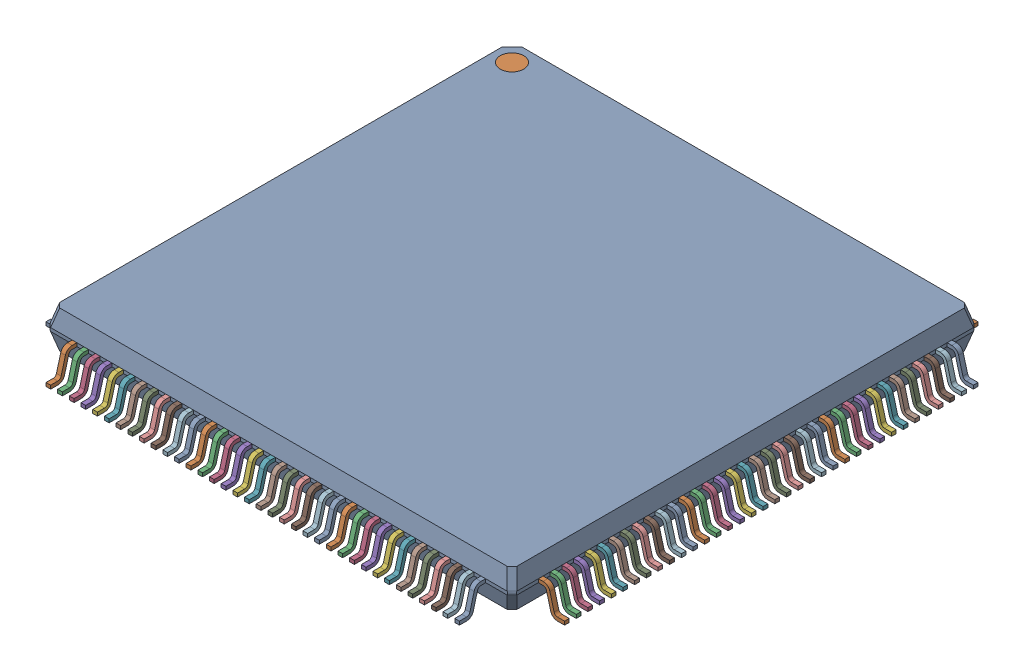
SolidWorks assembly User Library-LQFP144-3, configuration 默认. Lengths in mm.
Overall size (22.2 1.89 22.2).
146 component instances, 3 part files, 0 mates.
Components (placement in the parent):
- case-1: case [默认] at (0 1 0) size (19.96 1.6 19.96)
- pin-28-1: pin-28 [默认] at (-8.75 0.9224 9.9806) size (0.2 1.16 1.12)
- pin-28-2: pin-28 [默认] at (-8.25 0.9224 9.9806) size (0.2 1.16 1.12)
- pin-28-3: pin-28 [默认] at (-7.75 0.9224 9.9806) size (0.2 1.16 1.12)
- pin-28-4: pin-28 [默认] at (-7.25 0.9224 9.9806) size (0.2 1.16 1.12)
- pin-28-5: pin-28 [默认] at (-6.75 0.9224 9.9806) size (0.2 1.16 1.12)
- pin-28-6: pin-28 [默认] at (-6.25 0.9224 9.9806) size (0.2 1.16 1.12)
- pin-28-7: pin-28 [默认] at (-5.75 0.9224 9.9806) size (0.2 1.16 1.12)
- pin-28-8: pin-28 [默认] at (-5.25 0.9224 9.9806) size (0.2 1.16 1.12)
- pin-28-9: pin-28 [默认] at (-4.75 0.9224 9.9806) size (0.2 1.16 1.12)
- pin-28-10: pin-28 [默认] at (-4.25 0.9224 9.9806) size (0.2 1.16 1.12)
- pin-28-11: pin-28 [默认] at (-3.75 0.9224 9.9806) size (0.2 1.16 1.12)
- pin-28-12: pin-28 [默认] at (-3.25 0.9224 9.9806) size (0.2 1.16 1.12)
- pin-28-13: pin-28 [默认] at (-2.75 0.9224 9.9806) size (0.2 1.16 1.12)
- pin-28-14: pin-28 [默认] at (-2.25 0.9224 9.9806) size (0.2 1.16 1.12)
- pin-28-15: pin-28 [默认] at (-1.75 0.9224 9.9806) size (0.2 1.16 1.12)
- pin-28-16: pin-28 [默认] at (-1.25 0.9224 9.9806) size (0.2 1.16 1.12)
- pin-28-17: pin-28 [默认] at (-0.75 0.9224 9.9806) size (0.2 1.16 1.12)
- pin-28-18: pin-28 [默认] at (-0.25 0.9224 9.9806) size (0.2 1.16 1.12)
- pin-28-19: pin-28 [默认] at (0.25 0.9224 9.9806) size (0.2 1.16 1.12)
- pin-28-20: pin-28 [默认] at (0.75 0.9224 9.9806) size (0.2 1.16 1.12)
- pin-28-21: pin-28 [默认] at (1.25 0.9224 9.9806) size (0.2 1.16 1.12)
- pin-28-22: pin-28 [默认] at (1.75 0.9224 9.9806) size (0.2 1.16 1.12)
- pin-28-23: pin-28 [默认] at (2.25 0.9224 9.9806) size (0.2 1.16 1.12)
- pin-28-24: pin-28 [默认] at (2.75 0.9224 9.9806) size (0.2 1.16 1.12)
- pin-28-25: pin-28 [默认] at (3.25 0.9224 9.9806) size (0.2 1.16 1.12)
- pin-28-26: pin-28 [默认] at (3.75 0.9224 9.9806) size (0.2 1.16 1.12)
- pin-28-27: pin-28 [默认] at (4.25 0.9224 9.9806) size (0.2 1.16 1.12)
- pin-28-28: pin-28 [默认] at (4.75 0.9224 9.9806) size (0.2 1.16 1.12)
- pin-28-29: pin-28 [默认] at (5.25 0.9224 9.9806) size (0.2 1.16 1.12)
- pin-28-30: pin-28 [默认] at (5.75 0.9224 9.9806) size (0.2 1.16 1.12)
- pin-28-31: pin-28 [默认] at (6.25 0.9224 9.9806) size (0.2 1.16 1.12)
- pin-28-32: pin-28 [默认] at (6.75 0.9224 9.9806) size (0.2 1.16 1.12)
- pin-28-33: pin-28 [默认] at (7.25 0.9224 9.9806) size (0.2 1.16 1.12)
- pin-28-34: pin-28 [默认] at (7.75 0.9224 9.9806) size (0.2 1.16 1.12)
- pin-28-35: pin-28 [默认] at (8.25 0.9224 9.9806) size (0.2 1.16 1.12)
- pin-28-36: pin-28 [默认] at (8.75 0.9224 9.9806) size (0.2 1.16 1.12)
- pin-28-37: pin-28 [默认] at (9.9806 0.9224 8.75) x (0 0 -1) z (1 0 0) size (0.2 1.16 1.12)
- pin-28-38: pin-28 [默认] at (9.9806 0.9224 8.25) x (0 0 -1) z (1 0 0) size (0.2 1.16 1.12)
- pin-28-39: pin-28 [默认] at (9.9806 0.9224 7.75) x (0 0 -1) z (1 0 0) size (0.2 1.16 1.12)
- pin-28-40: pin-28 [默认] at (9.9806 0.9224 7.25) x (0 0 -1) z (1 0 0) size (0.2 1.16 1.12)
- pin-28-41: pin-28 [默认] at (9.9806 0.9224 6.75) x (0 0 -1) z (1 0 0) size (0.2 1.16 1.12)
- pin-28-42: pin-28 [默认] at (9.9806 0.9224 6.25) x (0 0 -1) z (1 0 0) size (0.2 1.16 1.12)
- pin-28-43: pin-28 [默认] at (9.9806 0.9224 5.75) x (0 0 -1) z (1 0 0) size (0.2 1.16 1.12)
- pin-28-44: pin-28 [默认] at (9.9806 0.9224 5.25) x (0 0 -1) z (1 0 0) size (0.2 1.16 1.12)
- pin-28-45: pin-28 [默认] at (9.9806 0.9224 4.75) x (0 0 -1) z (1 0 0) size (0.2 1.16 1.12)
- pin-28-46: pin-28 [默认] at (9.9806 0.9224 4.25) x (0 0 -1) z (1 0 0) size (0.2 1.16 1.12)
- pin-28-47: pin-28 [默认] at (9.9806 0.9224 3.75) x (0 0 -1) z (1 0 0) size (0.2 1.16 1.12)
- pin-28-48: pin-28 [默认] at (9.9806 0.9224 3.25) x (0 0 -1) z (1 0 0) size (0.2 1.16 1.12)
- pin-28-49: pin-28 [默认] at (9.9806 0.9224 2.75) x (0 0 -1) z (1 0 0) size (0.2 1.16 1.12)
- pin-28-50: pin-28 [默认] at (9.9806 0.9224 2.25) x (0 0 -1) z (1 0 0) size (0.2 1.16 1.12)
- pin-28-51: pin-28 [默认] at (9.9806 0.9224 1.75) x (0 0 -1) z (1 0 0) size (0.2 1.16 1.12)
- pin-28-52: pin-28 [默认] at (9.9806 0.9224 1.25) x (0 0 -1) z (1 0 0) size (0.2 1.16 1.12)
- pin-28-53: pin-28 [默认] at (9.9806 0.9224 0.75) x (0 0 -1) z (1 0 0) size (0.2 1.16 1.12)
- pin-28-54: pin-28 [默认] at (9.9806 0.9224 0.25) x (0 0 -1) z (1 0 0) size (0.2 1.16 1.12)
- pin-28-55: pin-28 [默认] at (9.9806 0.9224 -0.25) x (0 0 -1) z (1 0 0) size (0.2 1.16 1.12)
- pin-28-56: pin-28 [默认] at (9.9806 0.9224 -0.75) x (0 0 -1) z (1 0 0) size (0.2 1.16 1.12)
- pin-28-57: pin-28 [默认] at (9.9806 0.9224 -1.25) x (0 0 -1) z (1 0 0) size (0.2 1.16 1.12)
- pin-28-58: pin-28 [默认] at (9.9806 0.9224 -1.75) x (0 0 -1) z (1 0 0) size (0.2 1.16 1.12)
- pin-28-59: pin-28 [默认] at (9.9806 0.9224 -2.25) x (0 0 -1) z (1 0 0) size (0.2 1.16 1.12)
- pin-28-60: pin-28 [默认] at (9.9806 0.9224 -2.75) x (0 0 -1) z (1 0 0) size (0.2 1.16 1.12)
- pin-28-61: pin-28 [默认] at (9.9806 0.9224 -3.25) x (0 0 -1) z (1 0 0) size (0.2 1.16 1.12)
- pin-28-62: pin-28 [默认] at (9.9806 0.9224 -3.75) x (0 0 -1) z (1 0 0) size (0.2 1.16 1.12)
- pin-28-63: pin-28 [默认] at (9.9806 0.9224 -4.25) x (0 0 -1) z (1 0 0) size (0.2 1.16 1.12)
- pin-28-64: pin-28 [默认] at (9.9806 0.9224 -4.75) x (0 0 -1) z (1 0 0) size (0.2 1.16 1.12)
- pin-28-65: pin-28 [默认] at (9.9806 0.9224 -5.25) x (0 0 -1) z (1 0 0) size (0.2 1.16 1.12)
- pin-28-66: pin-28 [默认] at (9.9806 0.9224 -5.75) x (0 0 -1) z (1 0 0) size (0.2 1.16 1.12)
- pin-28-67: pin-28 [默认] at (9.9806 0.9224 -6.25) x (0 0 -1) z (1 0 0) size (0.2 1.16 1.12)
- pin-28-68: pin-28 [默认] at (9.9806 0.9224 -6.75) x (0 0 -1) z (1 0 0) size (0.2 1.16 1.12)
- pin-28-69: pin-28 [默认] at (9.9806 0.9224 -7.25) x (0 0 -1) z (1 0 0) size (0.2 1.16 1.12)
- pin-28-70: pin-28 [默认] at (9.9806 0.9224 -7.75) x (0 0 -1) z (1 0 0) size (0.2 1.16 1.12)
- pin-28-71: pin-28 [默认] at (9.9806 0.9224 -8.25) x (0 0 -1) z (1 0 0) size (0.2 1.16 1.12)
- pin-28-72: pin-28 [默认] at (9.9806 0.9224 -8.75) x (0 0 -1) z (1 0 0) size (0.2 1.16 1.12)
- pin-28-73: pin-28 [默认] at (8.75 0.9224 -9.9806) x (-1 0 0) z (0 0 -1) size (0.2 1.16 1.12)
- pin-28-74: pin-28 [默认] at (8.25 0.9224 -9.9806) x (-1 0 0) z (0 0 -1) size (0.2 1.16 1.12)
- pin-28-75: pin-28 [默认] at (7.75 0.9224 -9.9806) x (-1 0 0) z (0 0 -1) size (0.2 1.16 1.12)
- pin-28-76: pin-28 [默认] at (7.25 0.9224 -9.9806) x (-1 0 0) z (0 0 -1) size (0.2 1.16 1.12)
- pin-28-77: pin-28 [默认] at (6.75 0.9224 -9.9806) x (-1 0 0) z (0 0 -1) size (0.2 1.16 1.12)
- pin-28-78: pin-28 [默认] at (6.25 0.9224 -9.9806) x (-1 0 0) z (0 0 -1) size (0.2 1.16 1.12)
- pin-28-79: pin-28 [默认] at (5.75 0.9224 -9.9806) x (-1 0 0) z (0 0 -1) size (0.2 1.16 1.12)
- pin-28-80: pin-28 [默认] at (5.25 0.9224 -9.9806) x (-1 0 0) z (0 0 -1) size (0.2 1.16 1.12)
- pin-28-81: pin-28 [默认] at (4.75 0.9224 -9.9806) x (-1 0 0) z (0 0 -1) size (0.2 1.16 1.12)
- pin-28-82: pin-28 [默认] at (4.25 0.9224 -9.9806) x (-1 0 0) z (0 0 -1) size (0.2 1.16 1.12)
- pin-28-83: pin-28 [默认] at (3.75 0.9224 -9.9806) x (-1 0 0) z (0 0 -1) size (0.2 1.16 1.12)
- pin-28-84: pin-28 [默认] at (3.25 0.9224 -9.9806) x (-1 0 0) z (0 0 -1) size (0.2 1.16 1.12)
- pin-28-85: pin-28 [默认] at (2.75 0.9224 -9.9806) x (-1 0 0) z (0 0 -1) size (0.2 1.16 1.12)
- pin-28-86: pin-28 [默认] at (2.25 0.9224 -9.9806) x (-1 0 0) z (0 0 -1) size (0.2 1.16 1.12)
- pin-28-87: pin-28 [默认] at (1.75 0.9224 -9.9806) x (-1 0 0) z (0 0 -1) size (0.2 1.16 1.12)
- pin-28-88: pin-28 [默认] at (1.25 0.9224 -9.9806) x (-1 0 0) z (0 0 -1) size (0.2 1.16 1.12)
- pin-28-89: pin-28 [默认] at (0.75 0.9224 -9.9806) x (-1 0 0) z (0 0 -1) size (0.2 1.16 1.12)
- pin-28-90: pin-28 [默认] at (0.25 0.9224 -9.9806) x (-1 0 0) z (0 0 -1) size (0.2 1.16 1.12)
- pin-28-91: pin-28 [默认] at (-0.25 0.9224 -9.9806) x (-1 0 0) z (0 0 -1) size (0.2 1.16 1.12)
- pin-28-92: pin-28 [默认] at (-0.75 0.9224 -9.9806) x (-1 0 0) z (0 0 -1) size (0.2 1.16 1.12)
- pin-28-93: pin-28 [默认] at (-1.25 0.9224 -9.9806) x (-1 0 0) z (0 0 -1) size (0.2 1.16 1.12)
- pin-28-94: pin-28 [默认] at (-1.75 0.9224 -9.9806) x (-1 0 0) z (0 0 -1) size (0.2 1.16 1.12)
- pin-28-95: pin-28 [默认] at (-2.25 0.9224 -9.9806) x (-1 0 0) z (0 0 -1) size (0.2 1.16 1.12)
- pin-28-96: pin-28 [默认] at (-2.75 0.9224 -9.9806) x (-1 0 0) z (0 0 -1) size (0.2 1.16 1.12)
- pin-28-97: pin-28 [默认] at (-3.25 0.9224 -9.9806) x (-1 0 0) z (0 0 -1) size (0.2 1.16 1.12)
- pin-28-98: pin-28 [默认] at (-3.75 0.9224 -9.9806) x (-1 0 0) z (0 0 -1) size (0.2 1.16 1.12)
- pin-28-99: pin-28 [默认] at (-4.25 0.9224 -9.9806) x (-1 0 0) z (0 0 -1) size (0.2 1.16 1.12)
- pin-28-100: pin-28 [默认] at (-4.75 0.9224 -9.9806) x (-1 0 0) z (0 0 -1) size (0.2 1.16 1.12)
- pin-28-101: pin-28 [默认] at (-5.25 0.9224 -9.9806) x (-1 0 0) z (0 0 -1) size (0.2 1.16 1.12)
- pin-28-102: pin-28 [默认] at (-5.75 0.9224 -9.9806) x (-1 0 0) z (0 0 -1) size (0.2 1.16 1.12)
- pin-28-103: pin-28 [默认] at (-6.25 0.9224 -9.9806) x (-1 0 0) z (0 0 -1) size (0.2 1.16 1.12)
- pin-28-104: pin-28 [默认] at (-6.75 0.9224 -9.9806) x (-1 0 0) z (0 0 -1) size (0.2 1.16 1.12)
- pin-28-105: pin-28 [默认] at (-7.25 0.9224 -9.9806) x (-1 0 0) z (0 0 -1) size (0.2 1.16 1.12)
- pin-28-106: pin-28 [默认] at (-7.75 0.9224 -9.9806) x (-1 0 0) z (0 0 -1) size (0.2 1.16 1.12)
- pin-28-107: pin-28 [默认] at (-8.25 0.9224 -9.9806) x (-1 0 0) z (0 0 -1) size (0.2 1.16 1.12)
- pin-28-108: pin-28 [默认] at (-8.75 0.9224 -9.9806) x (-1 0 0) z (0 0 -1) size (0.2 1.16 1.12)
- pin-28-109: pin-28 [默认] at (-9.9806 0.9224 -8.75) x (0 0 1) z (-1 0 0) size (0.2 1.16 1.12)
- pin-28-110: pin-28 [默认] at (-9.9806 0.9224 -8.25) x (0 0 1) z (-1 0 0) size (0.2 1.16 1.12)
- pin-28-111: pin-28 [默认] at (-9.9806 0.9224 -7.75) x (0 0 1) z (-1 0 0) size (0.2 1.16 1.12)
- pin-28-112: pin-28 [默认] at (-9.9806 0.9224 -7.25) x (0 0 1) z (-1 0 0) size (0.2 1.16 1.12)
- pin-28-113: pin-28 [默认] at (-9.9806 0.9224 -6.75) x (0 0 1) z (-1 0 0) size (0.2 1.16 1.12)
- pin-28-114: pin-28 [默认] at (-9.9806 0.9224 -6.25) x (0 0 1) z (-1 0 0) size (0.2 1.16 1.12)
- pin-28-115: pin-28 [默认] at (-9.9806 0.9224 -5.75) x (0 0 1) z (-1 0 0) size (0.2 1.16 1.12)
- pin-28-116: pin-28 [默认] at (-9.9806 0.9224 -5.25) x (0 0 1) z (-1 0 0) size (0.2 1.16 1.12)
- pin-28-117: pin-28 [默认] at (-9.9806 0.9224 -4.75) x (0 0 1) z (-1 0 0) size (0.2 1.16 1.12)
- pin-28-118: pin-28 [默认] at (-9.9806 0.9224 -4.25) x (0 0 1) z (-1 0 0) size (0.2 1.16 1.12)
- pin-28-119: pin-28 [默认] at (-9.9806 0.9224 -3.75) x (0 0 1) z (-1 0 0) size (0.2 1.16 1.12)
- pin-28-120: pin-28 [默认] at (-9.9806 0.9224 -3.25) x (0 0 1) z (-1 0 0) size (0.2 1.16 1.12)
- pin-28-121: pin-28 [默认] at (-9.9806 0.9224 -2.75) x (0 0 1) z (-1 0 0) size (0.2 1.16 1.12)
- pin-28-122: pin-28 [默认] at (-9.9806 0.9224 -2.25) x (0 0 1) z (-1 0 0) size (0.2 1.16 1.12)
- pin-28-123: pin-28 [默认] at (-9.9806 0.9224 -1.75) x (0 0 1) z (-1 0 0) size (0.2 1.16 1.12)
- pin-28-124: pin-28 [默认] at (-9.9806 0.9224 -1.25) x (0 0 1) z (-1 0 0) size (0.2 1.16 1.12)
- pin-28-125: pin-28 [默认] at (-9.9806 0.9224 -0.75) x (0 0 1) z (-1 0 0) size (0.2 1.16 1.12)
- pin-28-126: pin-28 [默认] at (-9.9806 0.9224 -0.25) x (0 0 1) z (-1 0 0) size (0.2 1.16 1.12)
- pin-28-127: pin-28 [默认] at (-9.9806 0.9224 0.25) x (0 0 1) z (-1 0 0) size (0.2 1.16 1.12)
- pin-28-128: pin-28 [默认] at (-9.9806 0.9224 0.75) x (0 0 1) z (-1 0 0) size (0.2 1.16 1.12)
- pin-28-129: pin-28 [默认] at (-9.9806 0.9224 1.25) x (0 0 1) z (-1 0 0) size (0.2 1.16 1.12)
- pin-28-130: pin-28 [默认] at (-9.9806 0.9224 1.75) x (0 0 1) z (-1 0 0) size (0.2 1.16 1.12)
- pin-28-131: pin-28 [默认] at (-9.9806 0.9224 2.25) x (0 0 1) z (-1 0 0) size (0.2 1.16 1.12)
- pin-28-132: pin-28 [默认] at (-9.9806 0.9224 2.75) x (0 0 1) z (-1 0 0) size (0.2 1.16 1.12)
- pin-28-133: pin-28 [默认] at (-9.9806 0.9224 3.25) x (0 0 1) z (-1 0 0) size (0.2 1.16 1.12)
- pin-28-134: pin-28 [默认] at (-9.9806 0.9224 3.75) x (0 0 1) z (-1 0 0) size (0.2 1.16 1.12)
- pin-28-135: pin-28 [默认] at (-9.9806 0.9224 4.25) x (0 0 1) z (-1 0 0) size (0.2 1.16 1.12)
- pin-28-136: pin-28 [默认] at (-9.9806 0.9224 4.75) x (0 0 1) z (-1 0 0) size (0.2 1.16 1.12)
- pin-28-137: pin-28 [默认] at (-9.9806 0.9224 5.25) x (0 0 1) z (-1 0 0) size (0.2 1.16 1.12)
- pin-28-138: pin-28 [默认] at (-9.9806 0.9224 5.75) x (0 0 1) z (-1 0 0) size (0.2 1.16 1.12)
- pin-28-139: pin-28 [默认] at (-9.9806 0.9224 6.25) x (0 0 1) z (-1 0 0) size (0.2 1.16 1.12)
- pin-28-140: pin-28 [默认] at (-9.9806 0.9224 6.75) x (0 0 1) z (-1 0 0) size (0.2 1.16 1.12)
- pin-28-141: pin-28 [默认] at (-9.9806 0.9224 7.25) x (0 0 1) z (-1 0 0) size (0.2 1.16 1.12)
- pin-28-142: pin-28 [默认] at (-9.9806 0.9224 7.75) x (0 0 1) z (-1 0 0) size (0.2 1.16 1.12)
- pin-28-143: pin-28 [默认] at (-9.9806 0.9224 8.25) x (0 0 1) z (-1 0 0) size (0.2 1.16 1.12)
- pin-28-144: pin-28 [默认] at (-9.9806 0.9224 8.75) x (0 0 1) z (-1 0 0) size (0.2 1.16 1.12)
- circle-1: circle [默认] at (-9 1.7 -9) size (1 0.1 1)
